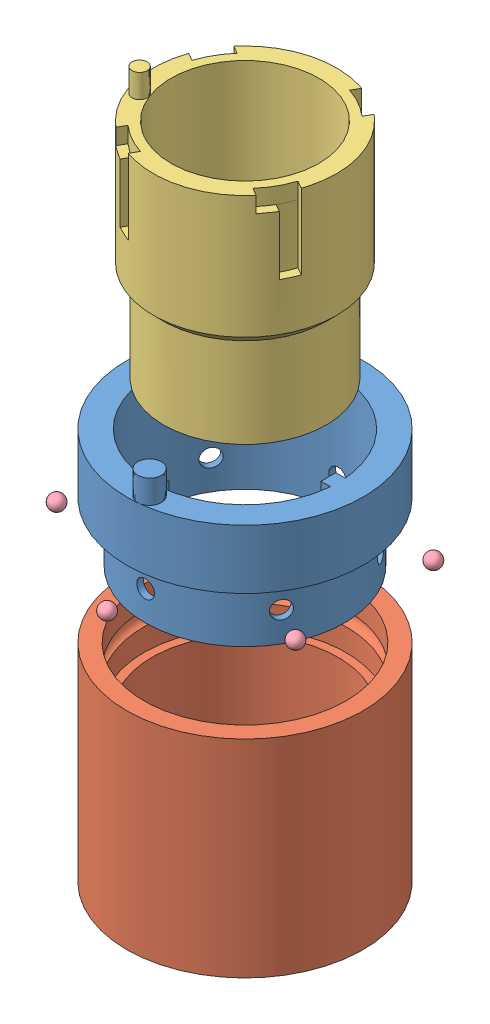
SolidWorks assembly proto for capstone, configuration Default. Lengths in mm.
Overall size (142.79 293.21 142.79).
9 component instances, 4 part files, 8 mates.
Components (placement in the parent):
- inner ring Rocket Shute deployment-1: inner ring Rocket Shute deployment [Default] at (-29.1326 56.5371 45.0188) size (101.6 60.96 101.6)
- outer ring rocket shute deployment-1: outer ring rocket shute deployment [Default] at (-68.8271 -23.0187 25.9203) x (0.624045 0 0.781388) z (-0.781388 0 0.624045) size (101.6 88.9 101.6)
- keeper ring2-1: keeper ring2 [Default] at (-29.1326 176.9742 -5.7812) x (0.869099 0 0.494637) z (0.494637 0 -0.869099) size (78.74 105.92 78.74)
- ball baring-1: ball baring [Default] at (-97.0039 24.1671 17.7823) x (0.893194 -0.308978 0.326705) z (-0.097258 -0.842089 -0.530497) size (6.35 6.35 6.35)
- ball baring-2: ball baring [Default] at (-17.1341 31.6809 58.4178) x (-0.647001 -0.71415 -0.26717) z (0.709702 -0.435926 -0.553436) size (6.35 6.35 6.35)
- ball baring-3: ball baring [Default] at (8.9899 22.5169 36.2278) x (0.710957 -0.219993 -0.667939) z (0.620191 0.643901 0.448057) size (6.35 6.35 6.35)
- ball baring-4: ball baring [Default] at (-40.1879 9.4958 -53.1199) x (0.596136 0.482145 -0.641995) z (0.577218 -0.813165 -0.074709) size (6.35 6.35 6.35)
- ball baring-5: ball baring [Default] at (-79.3152 13.1679 -53.1483) x (-0.060639 0.284136 0.956864) z (-0.966136 0.224166 -0.127792) size (6.35 6.35 6.35)
- ball baring-6: ball baring [Default] at (31.2188 21.1128 -19.4362) x (-0.487698 -0.14428 -0.861007) z (0.872896 -0.064521 -0.483621) size (6.35 6.35 6.35)
Mates (geometry in assembly coordinates):
- Concentric4: concentric: cylinder of keeper ring2-1 through (-29.1326 75.3742 -5.7812) axis (0 1 0) radius 39.37; cylinder of inner ring Rocket Shute deployment-1 through (-29.1326 56.5371 -5.7812) axis (0 -1 0) radius 40.005
- Concentric5: concentric: cylinder of inner ring Rocket Shute deployment-1 through (-29.1326 81.2055 -5.7812) axis (0 1 0) radius 42.8625; cylinder of outer ring rocket shute deployment-1 through (-29.1326 -51.332 -5.7812) axis (0 1 0) radius 43.434
- Concentric6: concentric: cylinder of inner ring Rocket Shute deployment-1 through (-57.155 18.4371 10.3975) axis (-0.866025 0 0.5) radius 3.81; sphere of ball baring-1
- Concentric7: concentric: cylinder of inner ring Rocket Shute deployment-1 through (-29.1326 18.4371 26.5762) axis (0 0 1) radius 3.81; sphere of ball baring-2
- Concentric8: concentric: cylinder of inner ring Rocket Shute deployment-1 through (-1.1102 18.4371 10.3975) axis (0.866025 0 0.5) radius 3.81; sphere of ball baring-3
- Concentric9: concentric: cylinder of inner ring Rocket Shute deployment-1 through (-1.1102 18.4371 -21.96) axis (0.866025 0 -0.5) radius 3.81; sphere of ball baring-6
- Concentric10: concentric: cylinder of inner ring Rocket Shute deployment-1 through (-29.1326 18.4371 -38.1387) axis (0 0 -1) radius 3.81; sphere of ball baring-4
- Concentric11: concentric: cylinder of inner ring Rocket Shute deployment-1 through (-57.155 18.4371 -21.96) axis (-0.866025 0 -0.5) radius 3.81; sphere of ball baring-5
